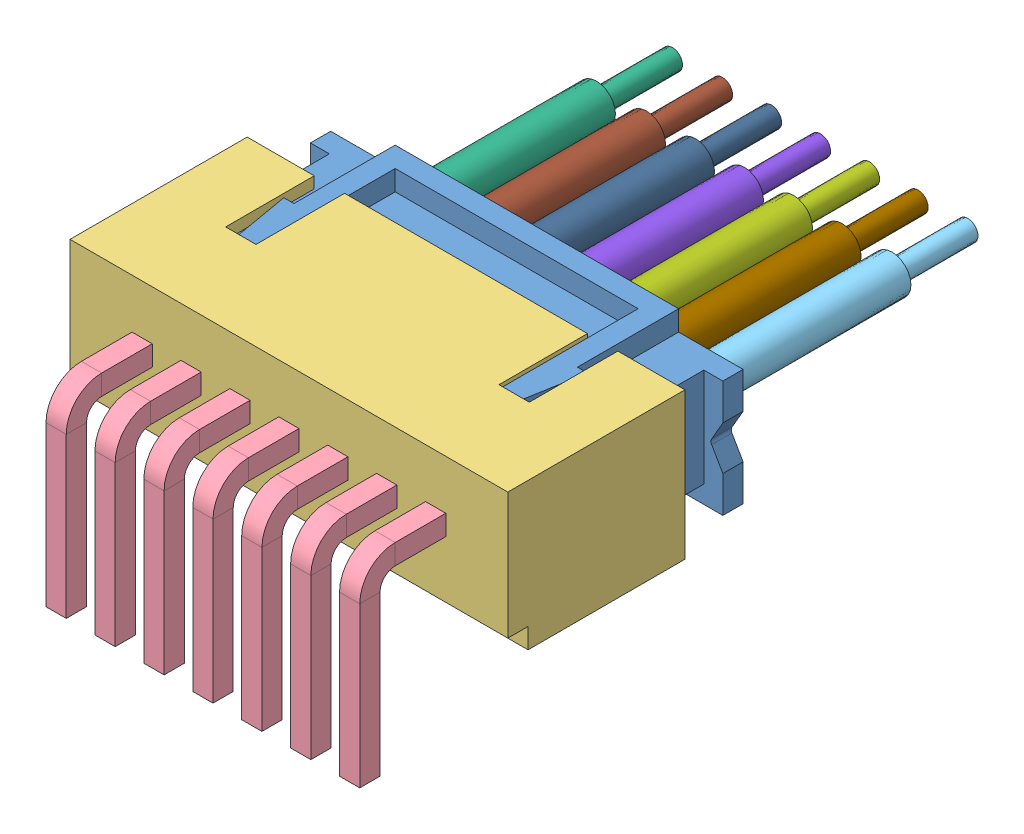
SolidWorks assembly Assem1, configuration Default. Lengths in mm.
Overall size (17.3 9.85 24.4).
23 component instances, 11 part files, 45 mates.
Components (placement in the parent):
- JST - XH MALE 7pin-1: JST - XH MALE 7pin [Default] at (7.5769 9.386 11.1264) size (16.3 5.4 8.4)
- Part1-1: Part1 [Default] at (11.4435 9.836 17.4264) x (1 0 0) z (0 1 0) size (1.8 6 3.23)
- Part1-2: Part1 [Default] at (9.5102 9.836 17.4264) x (1 0 0) z (0 1 0) size (1.8 6 3.23)
- Part1-3: Part1 [Default] at (5.6435 9.836 17.4264) x (1 0 0) z (0 1 0) size (1.8 6 3.23)
- Part1-4: Part1 [Default] at (7.5769 9.836 17.4264) x (1 0 0) z (0 1 0) size (1.8 6 3.23)
- Part1-5: Part1 [Default] at (3.7102 9.836 17.4264) x (1 0 0) z (0 1 0) size (1.8 6 3.23)
- Part1-6: Part1 [Default] at (1.7435 9.836 17.4264) x (1 0 0) z (0 1 0) size (1.8 6 3.23)
- Part1-7: Part1 [Default] at (13.4102 9.836 17.4264) x (1 0 0) z (0 1 0) size (1.8 6 3.23)
- Part 2-1: Part 2 [Default] at (7.5769 9.586 13.1264) x (-1 0 0) z (0 1 0) size (17.3 7 5.8)
- Part3-1: Part3 [Default] at (7.5769 10.136 23.1264) x (0 0 1) z (-1 0 0) size (9.7 7.9 0.8)
- Part3-2: Part3 [Default] at (13.3769 10.136 23.1264) x (0 0 1) z (-1 0 0) size (9.7 7.9 0.8)
- Part3-3: Part3 [Default] at (9.5102 10.136 23.1264) x (0 0 1) z (-1 0 0) size (9.7 7.9 0.8)
- Part3-4: Part3 [Default] at (5.6435 10.136 23.1264) x (0 0 1) z (-1 0 0) size (9.7 7.9 0.8)
- Part3-5: Part3 [Default] at (1.7769 10.136 23.1264) x (0 0 1) z (-1 0 0) size (9.7 7.9 0.8)
- Part3-6: Part3 [Default] at (11.4435 10.136 23.1264) x (0 0 1) z (-1 0 0) size (9.7 7.9 0.8)
- Part3-7: Part3 [Default] at (3.7102 10.136 23.1264) x (0 0 1) z (-1 0 0) size (9.7 7.9 0.8)
- Part4-1: Part4 [Default] at (13.4114 9.5453 2.1287) size (1.5 1.5 16)
- Part5-1: Part5 [Default] at (1.7301 9.554 2.1251) size (1.5 1.5 16)
- Part6-1: Part6 [Default] at (9.5179 9.5367 2.1242) size (1.5 1.5 16)
- Part7-1: Part7 [Default] at (7.5876 9.5343 2.1315) size (1.5 1.5 16)
- Part8-1: Part8 [Default] at (11.4364 9.5311 2.124) size (1.5 1.5 16)
- Part9-1: Part9 [Default] at (5.6445 9.5409 2.1241) size (1.5 1.5 16)
- Part10-1: Part10 [Default] at (3.7112 9.5225 2.1277) size (1.5 1.5 16)
Mates (geometry in assembly coordinates):
- Width1: width anti-aligned: plane of Part1-7 through (12.5102 8.686 15.3264) normal (-1 0 0); plane of Part1-7 through (14.3102 8.686 15.3264) normal (1 0 0); plane of JST - XH MALE 7pin-1 through (12.4435 11.236 17.8264) normal (1 0 0); plane of JST - XH MALE 7pin-1 through (14.3769 11.236 17.8264) normal (-1 0 0)
- Width2: width anti-aligned: plane of Part1-1 through (10.5435 8.686 15.3264) normal (-1 0 0); plane of Part1-1 through (12.3435 8.686 15.3264) normal (1 0 0); plane of JST - XH MALE 7pin-1 through (10.5102 11.236 17.8264) normal (1 0 0); plane of JST - XH MALE 7pin-1 through (12.3769 11.236 17.8264) normal (-1 0 0)
- Width3: width anti-aligned: plane of Part1-2 through (8.6102 8.686 15.3264) normal (-1 0 0); plane of Part1-2 through (10.4102 8.686 15.3264) normal (1 0 0); plane of JST - XH MALE 7pin-1 through (8.5769 11.236 17.8264) normal (1 0 0); plane of JST - XH MALE 7pin-1 through (10.4435 11.236 17.8264) normal (-1 0 0)
- Width4: width anti-aligned: plane of Part1-4 through (6.6769 8.686 15.3264) normal (-1 0 0); plane of Part1-4 through (8.4769 8.686 15.3264) normal (1 0 0); plane of JST - XH MALE 7pin-1 through (6.6435 11.236 17.8264) normal (1 0 0); plane of JST - XH MALE 7pin-1 through (8.5102 11.236 17.8264) normal (-1 0 0)
- Width5: width anti-aligned: plane of Part1-3 through (6.5435 8.686 15.3264) normal (1 0 0); plane of Part1-3 through (4.7435 8.686 15.3264) normal (-1 0 0); plane of JST - XH MALE 7pin-1 through (6.5769 11.236 17.8264) normal (-1 0 0); plane of JST - XH MALE 7pin-1 through (4.7102 11.236 17.8264) normal (1 0 0)
- Width6: width anti-aligned: plane of Part1-5 through (4.6102 8.686 15.3264) normal (1 0 0); plane of Part1-5 through (2.8102 8.686 15.3264) normal (-1 0 0); plane of JST - XH MALE 7pin-1 through (4.6435 11.236 17.8264) normal (-1 0 0); plane of JST - XH MALE 7pin-1 through (2.7769 11.236 17.8264) normal (1 0 0)
- Width7: width anti-aligned: plane of Part1-6 through (0.8435 8.686 15.3264) normal (-1 0 0); plane of Part1-6 through (2.6435 8.686 15.3264) normal (1 0 0); plane of JST - XH MALE 7pin-1 through (0.7769 11.236 17.8264) normal (1 0 0); plane of JST - XH MALE 7pin-1 through (2.7102 11.236 17.8264) normal (-1 0 0)
- Width8: width anti-aligned: plane of Part1-6 through (0.8435 10.986 15.3264) normal (0 1 0); plane of Part1-6 through (0.8435 8.686 15.3264) normal (0 -1 0); plane of JST - XH MALE 7pin-1 through (0.7769 11.236 17.8264) normal (0 -1 0); plane of JST - XH MALE 7pin-1 through (2.1769 8.436 17.8264) normal (0 1 0)
- Width9: width anti-aligned: plane of Part1-5 through (2.8102 10.986 15.3264) normal (0 1 0); plane of Part1-5 through (2.8102 8.686 15.3264) normal (0 -1 0); plane of JST - XH MALE 7pin-1 through (2.7769 11.236 17.8264) normal (0 -1 0); plane of JST - XH MALE 7pin-1 through (2.7769 8.436 17.8264) normal (0 1 0)
- Width10: width anti-aligned: plane of Part1-3 through (4.7435 10.986 15.3264) normal (0 1 0); plane of Part1-3 through (4.7435 8.686 15.3264) normal (0 -1 0); plane of JST - XH MALE 7pin-1 through (4.7102 11.236 17.8264) normal (0 -1 0); plane of JST - XH MALE 7pin-1 through (4.7102 8.436 17.8264) normal (0 1 0)
- Width11: width anti-aligned: plane of Part1-4 through (6.6769 10.986 15.3264) normal (0 1 0); plane of Part1-4 through (6.6769 8.686 15.3264) normal (0 -1 0); plane of JST - XH MALE 7pin-1 through (6.6435 11.236 17.8264) normal (0 -1 0); plane of JST - XH MALE 7pin-1 through (6.6435 8.436 17.8264) normal (0 1 0)
- Width12: width anti-aligned: plane of Part1-2 through (8.6102 10.986 15.3264) normal (0 1 0); plane of Part1-2 through (8.6102 8.686 15.3264) normal (0 -1 0); plane of JST - XH MALE 7pin-1 through (8.5769 11.236 17.8264) normal (0 -1 0); plane of JST - XH MALE 7pin-1 through (8.5769 8.436 17.8264) normal (0 1 0)
- Width13: width anti-aligned: plane of Part1-1 through (10.5435 10.986 15.3264) normal (0 1 0); plane of Part1-1 through (10.5435 8.686 15.3264) normal (0 -1 0); plane of JST - XH MALE 7pin-1 through (10.5102 11.236 17.8264) normal (0 -1 0); plane of JST - XH MALE 7pin-1 through (10.5102 8.436 17.8264) normal (0 1 0)
- Width14: width anti-aligned: plane of Part1-7 through (12.5102 10.986 15.3264) normal (0 1 0); plane of Part1-7 through (12.5102 8.686 15.3264) normal (0 -1 0); plane of JST - XH MALE 7pin-1 through (12.4435 11.236 17.8264) normal (0 -1 0); plane of JST - XH MALE 7pin-1 through (12.4435 8.436 17.8264) normal (0 1 0)
- Distance1: distance = 0.4 mm anti-aligned: plane of Part1-7 through (13.4102 9.836 17.4264) normal (0 0 1); plane of JST - XH MALE 7pin-1 through (7.5769 9.386 17.8264) normal (0 0 -1)
- Distance2: distance = 0.4 mm anti-aligned: plane of Part1-1 through (11.4435 9.836 17.4264) normal (0 0 1); plane of JST - XH MALE 7pin-1 through (7.5769 9.386 17.8264) normal (0 0 -1)
- Distance3: distance = 0.4 mm anti-aligned: plane of Part1-2 through (9.5102 9.836 17.4264) normal (0 0 1); plane of JST - XH MALE 7pin-1 through (7.5769 9.386 17.8264) normal (0 0 -1)
- Distance4: distance = 0.4 mm anti-aligned: plane of Part1-4 through (7.5769 9.836 17.4264) normal (0 0 1); plane of JST - XH MALE 7pin-1 through (7.5769 9.386 17.8264) normal (0 0 -1)
- Distance5: distance = 0.4 mm anti-aligned: plane of Part1-3 through (5.6435 9.836 17.4264) normal (0 0 1); plane of JST - XH MALE 7pin-1 through (7.5769 9.386 17.8264) normal (0 0 -1)
- Distance6: distance = 0.4 mm anti-aligned: plane of Part1-5 through (3.7102 9.836 17.4264) normal (0 0 1); plane of JST - XH MALE 7pin-1 through (7.5769 9.386 17.8264) normal (0 0 -1)
- Distance7: distance = 0.4 mm anti-aligned: plane of Part1-6 through (1.7435 9.836 17.4264) normal (0 0 1); plane of JST - XH MALE 7pin-1 through (7.5769 9.386 17.8264) normal (0 0 -1)
- Width15: width anti-aligned: plane of Part 2-1 through (0.0769 7.136 18.1264) normal (1 0 0); plane of Part 2-1 through (15.0769 7.136 18.1264) normal (-1 0 0); plane of JST - XH MALE 7pin-1 through (0.1769 7.236 18.1264) normal (-1 0 0); plane of JST - XH MALE 7pin-1 through (14.9769 7.236 18.1264) normal (1 0 0)
- Width16: width anti-aligned: plane of Part 2-1 through (15.0769 7.136 18.1264) normal (0 1 0); plane of Part 2-1 through (15.0769 12.036 18.1264) normal (0 -1 0); plane of JST - XH MALE 7pin-1 through (7.5769 7.636 11.1264) normal (0 -1 0); plane of JST - XH MALE 7pin-1 through (0.1769 11.536 18.1264) normal (0 1 0)
- LimitDistance1: limit distance = 0 mm anti-aligned: plane of Part 2-1 through (7.5769 9.586 18.1264) normal (0 0 -1); plane of JST - XH MALE 7pin-1 through (7.5769 9.386 18.1264) normal (0 0 1)
- Coincident2: coincident aligned: plane of Part3-5 through (2.1769 9.136 23.5264) normal (0 0 1); plane of Part3-7 through (4.1102 9.136 23.5264) normal (0 0 1)
- Coincident3: coincident aligned: plane of Part3-4 through (6.0435 9.136 23.5264) normal (0 0 1); plane of Part3-7 through (4.1102 9.136 23.5264) normal (0 0 1)
- Coincident4: coincident aligned: plane of Part3-1 through (7.9769 9.136 23.5264) normal (0 0 1); plane of Part3-4 through (6.0435 9.136 23.5264) normal (0 0 1)
- Coincident5: coincident aligned: plane of Part3-1 through (7.9769 9.136 23.5264) normal (0 0 1); plane of Part3-2 through (13.7769 9.136 23.5264) normal (0 0 1)
- Coincident6: coincident aligned: plane of Part3-2 through (13.7769 9.136 23.5264) normal (0 0 1); plane of Part3-6 through (11.8435 9.136 23.5264) normal (0 0 1)
- Coincident7: coincident aligned: plane of Part3-3 through (9.9102 9.136 23.5264) normal (0 0 1); plane of Part3-6 through (11.8435 9.136 23.5264) normal (0 0 1)
- Coincident8: coincident aligned: plane of Part3-5 through (2.1769 10.536 22.1264) normal (0 1 0); plane of Part3-7 through (4.1102 10.536 22.1264) normal (0 1 0)
- Coincident9: coincident aligned: plane of Part3-4 through (6.0435 10.536 22.1264) normal (0 1 0); plane of Part3-7 through (4.1102 10.536 22.1264) normal (0 1 0)
- Coincident10: coincident aligned: plane of Part3-1 through (7.9769 10.536 22.1264) normal (0 1 0); plane of Part3-4 through (6.0435 10.536 22.1264) normal (0 1 0)
- Coincident11: coincident aligned: plane of Part3-1 through (7.9769 10.536 22.1264) normal (0 1 0); plane of Part3-2 through (13.7769 10.536 22.1264) normal (0 1 0)
- Coincident12: coincident aligned: plane of Part3-2 through (13.7769 10.536 22.1264) normal (0 1 0); plane of Part3-6 through (11.8435 10.536 22.1264) normal (0 1 0)
- Coincident13: coincident aligned: plane of Part3-3 through (9.9102 10.536 22.1264) normal (0 1 0); plane of Part3-6 through (11.8435 10.536 22.1264) normal (0 1 0)
- Coincident14: coincident anti-aligned: plane of Part 2-1 through (1.3769 10.536 10.1264) normal (0 -1 0); plane of Part3-5 through (2.1769 10.536 22.1264) normal (0 1 0)
- Coincident15: coincident anti-aligned: plane of Part 2-1 through (2.1769 10.536 10.1264) normal (-1 0 0); plane of Part3-5 through (2.1769 10.536 22.1264) normal (1 0 0)
- Coincident16: coincident anti-aligned: plane of Part 2-1 through (4.1102 10.536 10.1264) normal (-1 0 0); plane of Part3-7 through (4.1102 10.536 22.1264) normal (1 0 0)
- Coincident17: coincident anti-aligned: plane of Part 2-1 through (6.0435 10.536 10.1264) normal (-1 0 0); plane of Part3-4 through (6.0435 10.536 22.1264) normal (1 0 0)
- Coincident18: coincident anti-aligned: plane of Part 2-1 through (7.9769 10.536 10.1264) normal (-1 0 0); plane of Part3-1 through (7.9769 10.536 22.1264) normal (1 0 0)
- Coincident19: coincident anti-aligned: plane of Part 2-1 through (9.9102 10.536 10.1264) normal (-1 0 0); plane of Part3-3 through (9.9102 10.536 22.1264) normal (1 0 0)
- Coincident20: coincident anti-aligned: plane of Part 2-1 through (11.8435 10.536 10.1264) normal (-1 0 0); plane of Part3-6 through (11.8435 10.536 22.1264) normal (1 0 0)
- Coincident21: coincident anti-aligned: plane of Part 2-1 through (13.7769 10.536 10.1264) normal (-1 0 0); plane of Part3-2 through (13.7769 10.536 22.1264) normal (1 0 0)
- Distance9: distance = 0.7 mm aligned: plane of Part 2-1 through (7.5769 9.586 13.1264) normal (0 0 -1); plane of Part3-5 through (1.7769 10.136 13.8264) normal (0 0 -1)
